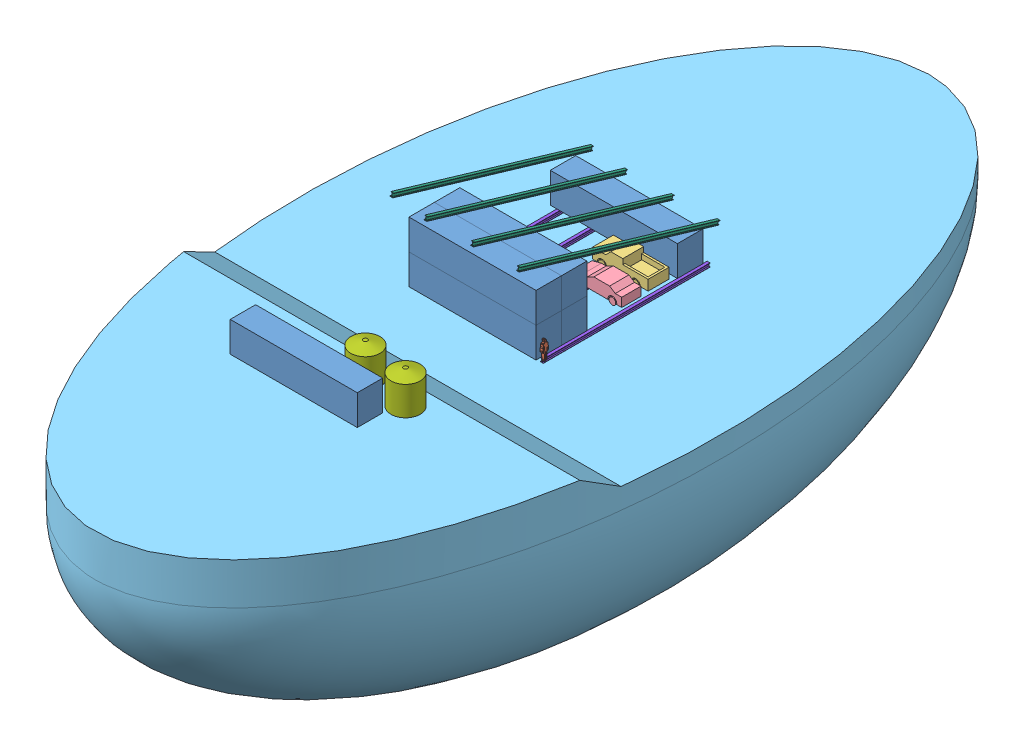
SolidWorks assembly container-house-assem, configuration Default. Lengths in mm.
Overall size (108994.63 68962.66 107221.29).
20 component instances, 8 part files, 31 mates.
Components (placement in the parent):
- 40ft-high-cube-container-1: 40ft-high-cube-container [Default] at (-358.5209 4134.6296 8146.5606) size (12192 2895.6 2438.4)
- 40ft-high-cube-container-2: 40ft-high-cube-container [Default] at (-358.5209 4134.6296 10584.9606) size (12192 2895.6 2438.4)
- 5-9-man-1: 5-9-man [Default] at (12377.982 4147.7022 12139.1742) x (0.043619 0 0.999048) z (0 -1 0) size (592.87 250 1775.51)
- 40ft-high-cube-container-3: 40ft-high-cube-container [Default] at (-358.5209 7030.2296 10584.9606) size (12192 2895.6 2438.4)
- 40ft-high-cube-container-4: 40ft-high-cube-container [Default] at (-358.5209 7030.2296 8146.5606) size (12192 2895.6 2438.4)
- 40ft-high-cube-container-5: 40ft-high-cube-container [Default] at (-358.5209 4134.6296 -2976.6394) size (12192 2895.6 2438.4)
- scale-F150-truck-1: scale-F150-truck [Default] at (6494.4791 5975.6296 262.4817) size (5339 1841 2007)
- scale-m3-tesla-car-1: scale-m3-tesla-car [Default] at (7139.4791 5587.6296 2951.1361) size (4694 1451.81 1850)
- land-1: land [Default] at (5918.3922 1134.6296 9423.6301) x (0.90569 0 -0.42394) z (0.42394 0 0.90569) size (83147.3 68962.66 79466.25)
- 20m-ibeam-1: 20m-ibeam [Default] at (7677.5813 7326.5871 -4122.118) x (1 0 0) z (0 0.284015 0.95882) size (280 360 20000)
- 20m-ibeam-2: 20m-ibeam [Default] at (134.422 7730.3422 -3928.57) x (1 0 0) z (0 0.284015 0.95882) size (280 360 20000)
- 20m-ibeam-4: 20m-ibeam [Default] at (3174.8447 7184.292 -4148.7579) x (1 0 0) z (0 0.284015 0.95882) size (280 360 20000)
- 20m-ibeam-5: 20m-ibeam [Default] at (11681.137 7050.2418 -4510.0832) x (1 0 0) z (0 0.284015 0.95882) size (280 360 20000)
- water-tank-1: water-tank [Default] at (6167.2194 5134.6296 23725.4705) size (2800 3200 2800)
- water-tank-2: water-tank [Default] at (10385.2533 5134.6296 24091.0226) size (2800 3200 2800)
- 16m-ibeam-3: 16m-ibeam [Default] at (7677.5813 3996.7806 -3548.2065) size (280 360 16000)
- 16m-ibeam-4: 16m-ibeam [Default] at (134.422 3996.7806 -3548.2065) size (280 360 16000)
- 16m-ibeam-5: 16m-ibeam [Default] at (11681.137 3996.7806 -3548.2065) size (280 360 16000)
- 16m-ibeam-6: 16m-ibeam [Default] at (3174.8447 3996.7806 -3548.2065) size (280 360 16000)
- 40ft-high-cube-container-6: 40ft-high-cube-container [Default] at (-1901.7714 5559.5493 26191.7124) size (12192 2895.6 2438.4)
Mates (geometry in assembly coordinates):
- Coincident1: coincident aligned: plane of 40ft-container-1 through (-358.5209 4134.6296 8146.5606) normal (0 -1 0); plane of 40ft-container-2 through (-358.5209 4134.6296 10584.9606) normal (0 -1 0)
- Coincident2: coincident aligned: plane of 40ft-container-1 through (-358.5209 7030.2296 8146.5606) normal (-1 0 0); plane of 40ft-container-2 through (-358.5209 7030.2296 10584.9606) normal (-1 0 0)
- Parallel1: parallel anti-aligned: line of 40ft-high-cube-container-2 through (11833.4791 7030.2296 13023.3606) axis (0 -1 0); line of 5-9-man-1 through (12271.3367 4106.8679 12676.9202) axis (0 1 0)
- Coincident4: coincident anti-aligned: plane of 40ft-high-cube-container-2 through (-358.5209 7030.2296 10584.9606) normal (0 1 0); plane of 40ft-high-cube-container-3 through (-358.5209 7030.2296 10584.9606) normal (0 -1 0)
- Coincident5: coincident anti-aligned: plane of 40ft-high-cube-container-1 through (-358.5209 7030.2296 10584.9606) normal (0 0 1); plane of 40ft-high-cube-container-2 through (-358.5209 7030.2296 10584.9606) normal (0 0 -1)
- Coincident6: coincident aligned: plane of 40ft-high-cube-container-2 through (11833.4791 7030.2296 10584.9606) normal (1 0 0); plane of 40ft-high-cube-container-3 through (11833.4791 9925.8296 10584.9606) normal (1 0 0)
- Coincident7: coincident aligned: plane of 40ft-high-cube-container-2 through (-358.5209 7030.2296 13023.3606) normal (0 0 1); plane of 40ft-high-cube-container-3 through (-358.5209 9925.8296 13023.3606) normal (0 0 1)
- Coincident8: coincident anti-aligned: plane of 40ft-high-cube-container-3 through (-358.5209 9925.8296 10584.9606) normal (0 0 -1); plane of 40ft-high-cube-container-4 through (-358.5209 9925.8296 10584.9606) normal (0 0 1)
- Coincident9: coincident anti-aligned: plane of 40ft-high-cube-container-1 through (-358.5209 7030.2296 8146.5606) normal (0 1 0); plane of 40ft-high-cube-container-4 through (-358.5209 7030.2296 8146.5606) normal (0 -1 0)
- Coincident10: coincident aligned: plane of 40ft-high-cube-container-1 through (11833.4791 7030.2296 8146.5606) normal (1 0 0); plane of 40ft-high-cube-container-4 through (11833.4791 9925.8296 8146.5606) normal (1 0 0)
- Coincident11: coincident aligned: plane of 40ft-high-cube-container-1 through (-358.5209 4134.6296 8146.5606) normal (0 -1 0); plane of 40ft-high-cube-container-5 through (-358.5209 4134.6296 -2976.6394) normal (0 -1 0)
- Distance1: distance = 16000 mm anti-aligned: plane of 40ft-high-cube-container-5 through (-358.5209 7030.2296 -2976.6394) normal (0 0 -1); plane of 40ft-high-cube-container-2 through (-358.5209 7030.2296 13023.3606) normal (0 0 1)
- Coincident13: coincident aligned: plane of 40ft-high-cube-container-1 through (11833.4791 7030.2296 8146.5606) normal (1 0 0); plane of 40ft-high-cube-container-5 through (11833.4791 7030.2296 -2976.6394) normal (1 0 0)
- Distance2: distance = 350 mm aligned: plane of scale-F150-truck-1 through (6494.4791 4484.6296 2269.4817) normal (0 -1 0); plane of 40ft-high-cube-container-5 through (-358.5209 4134.6296 -2976.6394) normal (0 -1 0)
- Coincident15: coincident aligned: plane of 40ft-high-cube-container-5 through (11833.4791 7030.2296 -2976.6394) normal (1 0 0); plane of scale-F150-truck-1 through (11833.4791 5975.6296 2269.4817) normal (1 0 0)
- Distance3: distance = 260 mm aligned: plane of scale-m3-tesla-car-1 through (7139.4791 4394.6296 4801.1361) normal (0 -1 0); plane of 40ft-high-cube-container-1 through (-358.5209 4134.6296 8146.5606) normal (0 -1 0)
- Coincident17: coincident aligned: plane of 40ft-high-cube-container-5 through (11833.4791 7030.2296 -2976.6394) normal (1 0 0); plane of scale-m3-tesla-car-1 through (11833.4791 5587.6296 4801.1361) normal (1 0 0)
- Distance4: distance = 1000 mm anti-aligned: plane of land-1 through (5918.3922 3134.6296 9423.6301) normal (0 1 0); plane of 40ft-high-cube-container-1 through (-358.5209 4134.6296 8146.5606) normal (0 -1 0)
- Parallel3: parallel aligned: line of 40ft-high-cube-container-1 through (11833.4791 4134.6296 10584.9606) axis (0 0 -1); line of land-1 through (5918.3922 1134.6296 49423.6301) axis (0 0 -1)
- Coincident20: coincident anti-aligned: plane of land-1 through (5918.3922 5134.6296 9423.6301) normal (0 1 0); plane of water-tank-1 through (6167.2194 5134.6296 23725.4705) normal (0 -1 0)
- Coincident21: coincident anti-aligned: plane of land-1 through (5918.3922 5134.6296 9423.6301) normal (0 1 0); plane of water-tank-2 through (10385.2533 5134.6296 24091.0226) normal (0 -1 0)
- Coincident24: coincident aligned: plane of 20m-ibeam-1 through (7833.5813 13006.894 15054.2767) normal (1 0 0); plane of 16m-ibeam-3 through (7833.5813 3996.7806 12451.7935) normal (1 0 0)
- Coincident25: coincident aligned: plane of 20m-ibeam-2 through (290.422 13410.6491 15247.8247) normal (1 0 0); plane of 16m-ibeam-4 through (290.422 3996.7806 12451.7935) normal (1 0 0)
- Coincident26: coincident aligned: plane of 20m-ibeam-5 through (11837.137 12730.5487 14666.3115) normal (1 0 0); plane of 16m-ibeam-5 through (11837.137 3996.7806 12451.7935) normal (1 0 0)
- Coincident27: coincident aligned: plane of 20m-ibeam-4 through (3330.8447 12864.5989 15027.6368) normal (1 0 0); plane of 16m-ibeam-6 through (3330.8447 3996.7806 12451.7935) normal (1 0 0)
- Coincident28: coincident aligned: plane of 16m-ibeam-5 through (11681.137 3996.7806 12451.7935) normal (0 1 0); plane of 16m-ibeam-6 through (3174.8447 3996.7806 12451.7935) normal (0 1 0)
- Coincident30: coincident aligned: plane of 16m-ibeam-4 through (134.422 3996.7806 12451.7935) normal (0 1 0); plane of 16m-ibeam-5 through (11681.137 3996.7806 12451.7935) normal (0 1 0)
- Coincident31: coincident aligned: plane of 16m-ibeam-3 through (7677.5813 3996.7806 12451.7935) normal (0 1 0); plane of 16m-ibeam-6 through (3174.8447 3996.7806 12451.7935) normal (0 1 0)
- Coincident33: coincident aligned: plane of 16m-ibeam-3 through (7677.5813 3996.7806 -3548.2065) normal (0 0 -1); plane of 16m-ibeam-5 through (11681.137 3996.7806 -3548.2065) normal (0 0 -1)
- Coincident34: coincident aligned: plane of 16m-ibeam-3 through (7677.5813 3996.7806 -3548.2065) normal (0 0 -1); plane of 16m-ibeam-6 through (3174.8447 3996.7806 -3548.2065) normal (0 0 -1)
- Coincident35: coincident aligned: plane of 16m-ibeam-3 through (7677.5813 3996.7806 -3548.2065) normal (0 0 -1); plane of 16m-ibeam-4 through (134.422 3996.7806 -3548.2065) normal (0 0 -1)
